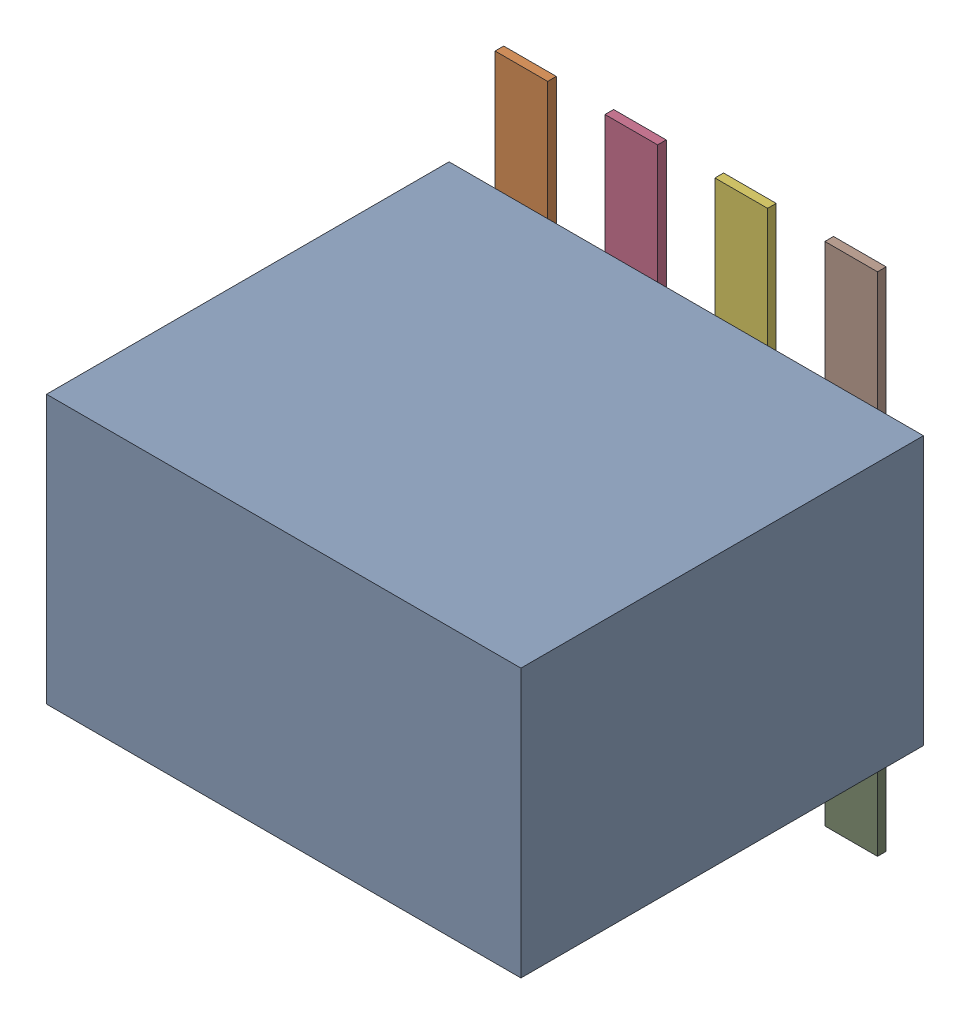
SolidWorks assembly 9705581488, configuration Default. Lengths in mm.
Overall size (5.48 5.85 4.75).
2 component instances, 2 part files, 0 mates.
Components (placement in the parent):
- Body-1: Body [Default] at (0 0 0.1) size (5.48 3.1 4.65)
- Pins-1: Pins [Default] at origin size (4.42 5.85 0.1)
